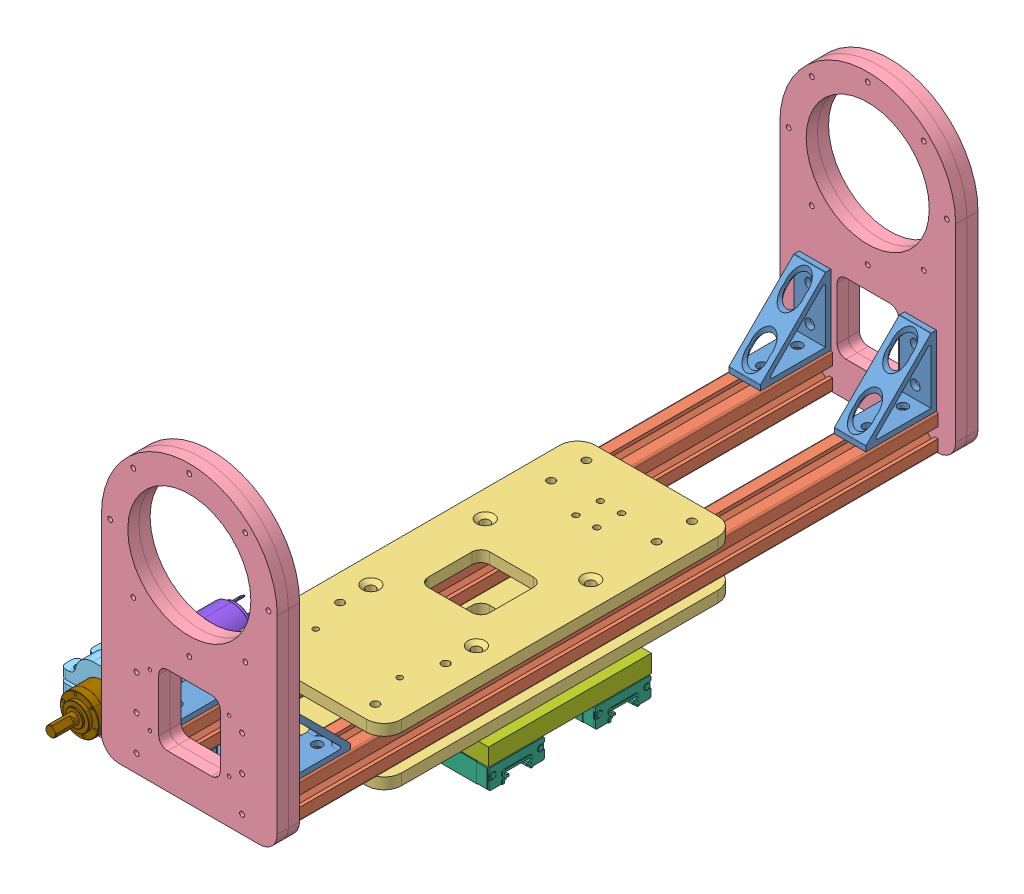
SolidWorks assembly teststand_TR2, configuration Default. Lengths in mm.
Overall size (137.28 196.05 414.76).
22 component instances, 10 part files, 39 mates.
Components (placement in the parent):
- 5537T658_T-SLOTTED FRAMING-1: 5537T658_T-SLOTTED FRAMING [5537T658] at (76.9939 380.9835 398.9275) x (0 0 -1) z (1 0 0) size (40 40 18)
- KHFS5-2020-4000-1: KHFS5-2020-4000 [14"] at (76.9939 370.9835 4025.865) size (20 20 373.06)
- teststand_TR2_adapter_Plate_Delrin-1: teststand_TR2_adapter_Plate_Delrin [Default] at (106.9939 354.6335 245.865) x (0 0 1) z (-1 0 0) size (200 6.35 90)
- teststand_TR2_Fram1-1: teststand_TR2_Fram1 [Default] at (106.9939 478.6835 19.515) size (100 167.7 6.35)
- teststand_TR2_testrig_clamp-1: teststand_TR2_testrig_clamp [Default] at (59.9939 373.4835 386.4275) x (0 0 -1) z (1 0 0) size (25 39.34 66.07)
- teststand_base_SSEB16_b_4-1: teststand_base_SSEB16_b_4 [Default] at (76.9939 328.6335 276.115) x (0 0 -1) z (1 0 0) size (32 12 42.4)
- teststand_TR2_adapter_Plate2-1: teststand_TR2_adapter_Plate2 [Default] at (106.9939 344.6335 245.865) size (101.4 10 92.5)
- KHFS5-2020-4000-2: KHFS5-2020-4000 [14"] at (136.9939 370.9835 4025.865) size (20 20 373.06)
- teststand_TR2_Fram1-2: teststand_TR2_Fram1 [Default] at (106.9939 478.6835 398.9275) size (100 167.7 6.35)
- 5537T658_T-SLOTTED FRAMING-2: 5537T658_T-SLOTTED FRAMING [5537T658] at (136.9939 380.9835 398.9275) x (0 0 -1) z (1 0 0) size (40 40 18)
- 5537T658_T-SLOTTED FRAMING-3: 5537T658_T-SLOTTED FRAMING [5537T658] at (136.9939 380.9835 25.865) x (0 0 1) z (-1 0 0) size (40 40 18)
- 5537T658_T-SLOTTED FRAMING-4: 5537T658_T-SLOTTED FRAMING [5537T658] at (76.9939 380.9835 25.865) x (0 0 1) z (-1 0 0) size (40 40 18)
- 302534_RE25_GB_20W_KL_2WE-1: 302534_RE25_GB_20W_KL_2WE [Default] at (44.4939 373.4835 366.1375) x (0 0 -1) z (1 0 0) size (78.61 25 25)
- 370792_GP22HP_3_4NM_4ST_KL-1: 370792_GP22HP_3_4NM_4ST_KL [Default] at (44.4939 373.4835 411.6275) x (0 0 -1) z (0.699856 -0.714284 0) size (62 22 22)
- teststand_base_SSEB16_b_4-2: teststand_base_SSEB16_b_4 [Default] at (136.9939 328.6335 276.115) x (0 0 -1) z (1 0 0) size (32 12 42.4)
- teststand_base_SSEB16_b_4-3: teststand_base_SSEB16_b_4 [Default] at (76.9939 328.6335 215.615) x (0 0 -1) z (1 0 0) size (32 12 42.4)
- teststand_base_SSEB16_b_4-4: teststand_base_SSEB16_b_4 [Default] at (136.9939 328.6335 215.615) x (0 0 -1) z (1 0 0) size (32 12 42.4)
- teststand_TR2_adapter_Plate_Delrin-2: teststand_TR2_adapter_Plate_Delrin [Default] at (106.9939 380.9835 245.865) x (0 0 1) z (-1 0 0) size (200 6.35 90)
- teststand_TR2_Fram1-3: teststand_TR2_Fram1 [Default] at (106.9939 478.6835 13.165) size (100 167.7 6.35)
- teststand_TR2_Fram1-4: teststand_TR2_Fram1 [Default] at (106.9939 478.6835 405.2775) size (100 167.7 6.35)
- teststand_TR2_testrig_clamp-2: teststand_TR2_testrig_clamp [Default] at (59.9939 373.4835 358.4275) x (0 0 -1) z (1 0 0) size (25 39.34 66.07)
- teststand_beltclamp-1: teststand_beltclamp [Default] at (106.9939 353.6335 178.865) x (0 0 -1) z (1 0 0) size (22 3 20)
Mates (geometry in assembly coordinates):
- Coincident14: coincident: plane of 5537T658_T-SLOTTED FRAMING-1 through (85.9939 380.9835 398.9275) normal (0 0 1); plane of teststand_TR2_Fram1-2 through (106.9939 478.6835 398.9275) normal (0 0 -1)
- Concentric12: concentric: cylinder of 5537T658_T-SLOTTED FRAMING-1 through (76.9939 390.9835 380.9275) axis (0 0 1) radius 2.75; cylinder of teststand_TR2_Fram1-2 through (76.9939 390.9835 405.2775) axis (0 0 1) radius 1.4
- Concentric13: concentric: cylinder of 5537T658_T-SLOTTED FRAMING-1 through (76.9939 410.9835 380.9275) axis (0 0 1) radius 2.75; cylinder of teststand_TR2_Fram1-2 through (76.9939 410.9835 405.2775) axis (0 0 1) radius 1.4
- Coincident10: coincident: plane of KHFS5-2020-4000-1 through (67.9939 360.9835 25.865) normal (0 -1 0); plane of teststand_TR2_adapter_Plate_Delrin-1 through (106.9939 360.9835 245.865) normal (0 1 0)
- Width5: width = 120 mm: plane of KHFS5-2020-4000-1 through (67.9939 361.9835 25.865) normal (0 0 -1); plane of KHFS5-2020-4000-1 through (67.9939 361.9835 398.9275) normal (0 0 1); plane of teststand_TR2_adapter_Plate_Delrin-1 through (61.9939 360.9835 145.865) normal (0 0 -1); plane of teststand_TR2_adapter_Plate_Delrin-1 through (61.9939 360.9835 345.865) normal (0 0 1)
- Coincident12: coincident: plane of KHFS5-2020-4000-1 through (67.9939 361.9835 25.865) normal (0 0 -1); plane of teststand_TR2_Fram1-1 through (106.9939 478.6835 25.865) normal (0 0 1)
- Concentric8: concentric: cylinder of KHFS5-2020-4000-1 through (76.9939 370.9835 25.865) axis (0 0 1) radius 2.1; cylinder of teststand_TR2_Fram1-1 through (76.9939 370.9835 25.865) axis (0 0 1) radius 1.4
- Width7: width: plane of teststand_TR2_adapter_Plate_Delrin-1 through (151.9939 360.9835 145.865) normal (1 0 0); plane of teststand_TR2_adapter_Plate_Delrin-1 through (61.9939 360.9835 145.865) normal (-1 0 0); plane of KHFS5-2020-4000-1 through (66.9939 367.9835 25.865) normal (-1 0 0); plane of KHFS5-2020-4000-2 through (146.9939 361.9835 25.865) normal (1 0 0)
- Coincident13: coincident: plane of KHFS5-2020-4000-1 through (67.9939 361.9835 398.9275) normal (0 0 1); plane of teststand_TR2_Fram1-2 through (106.9939 478.6835 398.9275) normal (0 0 -1)
- Concentric10: concentric: cylinder of KHFS5-2020-4000-1 through (76.9939 370.9835 25.865) axis (0 0 1) radius 2.1; cylinder of teststand_TR2_Fram1-2 through (76.9939 370.9835 405.2775) axis (0 0 1) radius 1.4
- Coincident18: coincident: plane of KHFS5-2020-4000-1 through (66.9939 367.9835 25.865) normal (-1 0 0); plane of teststand_TR2_testrig_clamp-1 through (66.9939 373.4835 386.4275) normal (1 0 0)
- Coincident19: coincident: plane of KHFS5-2020-4000-1 through (67.9939 360.9835 25.865) normal (0 -1 0); plane of teststand_TR2_testrig_clamp-1 through (86.9939 360.9835 398.9275) normal (0 1 0)
- Coincident9: coincident: plane of teststand_TR2_adapter_Plate_Delrin-1 through (106.9939 354.6335 245.865) normal (0 -1 0); plane of teststand_TR2_adapter_Plate2-1 through (106.9939 354.6335 245.865) normal (0 1 0)
- Concentric6: concentric: cylinder of teststand_TR2_adapter_Plate_Delrin-1 through (76.9939 360.9835 213.365) axis (0 1 0) radius 2.5527; cylinder of teststand_TR2_adapter_Plate2-1 through (76.9939 354.6335 213.365) axis (0 -1 0) radius 2
- Concentric7: concentric: cylinder of teststand_TR2_adapter_Plate_Delrin-1 through (136.9939 360.9835 278.365) axis (0 1 0) radius 2.5527; cylinder of teststand_TR2_adapter_Plate2-1 through (136.9939 354.6335 278.365) axis (0 -1 0) radius 2
- Coincident11: coincident: plane of teststand_TR2_adapter_Plate_Delrin-1 through (106.9939 360.9835 245.865) normal (0 1 0); plane of KHFS5-2020-4000-2 through (139.9939 360.9835 25.865) normal (0 -1 0)
- Width6: width = 120 mm: plane of KHFS5-2020-4000-2 through (127.9939 361.9835 25.865) normal (0 0 -1); plane of KHFS5-2020-4000-2 through (127.9939 361.9835 398.9275) normal (0 0 1); plane of teststand_TR2_adapter_Plate_Delrin-1 through (61.9939 360.9835 145.865) normal (0 0 -1); plane of teststand_TR2_adapter_Plate_Delrin-1 through (61.9939 360.9835 345.865) normal (0 0 1)
- Concentric9: concentric: cylinder of teststand_TR2_Fram1-1 through (136.9939 370.9835 25.865) axis (0 0 1) radius 1.4; cylinder of KHFS5-2020-4000-2 through (136.9939 370.9835 25.865) axis (0 0 1) radius 2.1
- Coincident16: coincident: plane of teststand_TR2_Fram1-1 through (106.9939 478.6835 25.865) normal (0 0 1); plane of 5537T658_T-SLOTTED FRAMING-3 through (127.9939 380.9835 25.865) normal (0 0 -1)
- Coincident17: coincident: plane of teststand_TR2_Fram1-1 through (106.9939 478.6835 25.865) normal (0 0 1); plane of 5537T658_T-SLOTTED FRAMING-4 through (67.9939 380.9835 25.865) normal (0 0 -1)
- Concentric16: concentric: cylinder of teststand_TR2_Fram1-1 through (76.9939 390.9835 25.865) axis (0 0 1) radius 1.4; cylinder of 5537T658_T-SLOTTED FRAMING-4 through (76.9939 390.9835 43.865) axis (0 0 -1) radius 2.75
- Concentric17: concentric: cylinder of teststand_TR2_Fram1-1 through (76.9939 410.9835 25.865) axis (0 0 1) radius 1.4; cylinder of 5537T658_T-SLOTTED FRAMING-4 through (76.9939 410.9835 43.865) axis (0 0 -1) radius 2.75
- Concentric18: concentric: cylinder of teststand_TR2_Fram1-1 through (136.9939 410.9835 25.865) axis (0 0 1) radius 1.4; cylinder of 5537T658_T-SLOTTED FRAMING-3 through (136.9939 410.9835 43.865) axis (0 0 -1) radius 2.75
- Concentric19: concentric: cylinder of teststand_TR2_Fram1-1 through (136.9939 390.9835 25.865) axis (0 0 1) radius 1.4; cylinder of 5537T658_T-SLOTTED FRAMING-3 through (136.9939 390.9835 43.865) axis (0 0 -1) radius 2.75
- Coincident20: coincident: plane of teststand_TR2_testrig_clamp-1 through (66.9939 355.9835 398.9275) normal (0 0 1); plane of teststand_TR2_Fram1-2 through (106.9939 478.6835 398.9275) normal (0 0 -1)
- Concentric21: concentric: cylinder of teststand_TR2_testrig_clamp-1 through (44.4939 373.4835 373.9275) axis (0 0 1) radius 11.075; cylinder of 370792_GP22HP_3_4NM_4ST_KL-1 through (44.4939 373.4835 427.9275) axis (0 0 -1) radius 11
- Coincident8: coincident: plane of teststand_base_SSEB16_b_4-1 through (90.6939 344.6335 283.915) normal (0 1 0); plane of teststand_TR2_adapter_Plate2-1 through (106.9939 344.6335 245.865) normal (0 -1 0)
- Concentric1: concentric: cylinder of teststand_base_SSEB16_b_4-3 through (66.9939 336.9236 203.115) axis (0 1 0) radius 1.2295; cylinder of teststand_TR2_adapter_Plate2-1 through (66.9939 354.6335 203.115) axis (0 -1 0) radius 1.5
- Concentric3: concentric: cylinder of teststand_base_SSEB16_b_4-2 through (146.9939 336.9236 288.615) axis (0 1 0) radius 1.2295; cylinder of teststand_TR2_adapter_Plate2-1 through (146.9939 354.6335 288.615) axis (0 -1 0) radius 1.5
- Concentric11: concentric: cylinder of KHFS5-2020-4000-2 through (136.9939 370.9835 25.865) axis (0 0 1) radius 2.1; cylinder of teststand_TR2_Fram1-2 through (136.9939 370.9835 405.2775) axis (0 0 1) radius 1.4
- Concentric14: concentric: cylinder of teststand_TR2_Fram1-2 through (136.9939 410.9835 405.2775) axis (0 0 1) radius 1.4; cylinder of 5537T658_T-SLOTTED FRAMING-2 through (136.9939 410.9835 380.9275) axis (0 0 1) radius 2.75
- Concentric15: concentric: cylinder of teststand_TR2_Fram1-2 through (136.9939 390.9835 405.2775) axis (0 0 1) radius 1.4; cylinder of 5537T658_T-SLOTTED FRAMING-2 through (136.9939 390.9835 380.9275) axis (0 0 1) radius 2.75
- Coincident15: coincident: plane of teststand_TR2_Fram1-2 through (106.9939 478.6835 398.9275) normal (0 0 -1); plane of 5537T658_T-SLOTTED FRAMING-2 through (145.9939 380.9835 398.9275) normal (0 0 1)
- Coincident21: coincident: plane of 302534_RE25_GB_20W_KL_2WE-1 through (44.4939 373.4835 365.9275) normal (0 0 1); plane of 370792_GP22HP_3_4NM_4ST_KL-1 through (44.4939 373.4835 365.9275) normal (0 0 -1)
- Concentric20: concentric: cylinder of 302534_RE25_GB_20W_KL_2WE-1 through (44.4939 373.4835 367.951) axis (0 0 -1) radius 12.5; cylinder of 370792_GP22HP_3_4NM_4ST_KL-1 through (44.4939 373.4835 427.9275) axis (0 0 -1) radius 11
- Coincident23: coincident: plane of teststand_TR2_Fram1-4 through (106.9939 478.6835 411.6275) normal (0 0 1); plane of 370792_GP22HP_3_4NM_4ST_KL-1 through (44.4939 373.4835 411.6275) normal (0 0 1)
- Distance1: distance = 30 mm: plane of teststand_TR2_adapter_Plate_Delrin-1 through (61.9939 360.9835 145.865) normal (0 0 -1); plane of teststand_beltclamp-1 through (116.9939 354.6335 175.865) normal (0 0 1)
- Coincident24: coincident: plane of teststand_TR2_adapter_Plate_Delrin-1 through (106.9939 354.6335 245.865) normal (0 -1 0); plane of teststand_beltclamp-1 through (116.9939 354.6335 175.865) normal (0 1 0); plane of teststand_beltclamp-1; plane of teststand_TR2_adapter_Plate_Delrin-1
- Distance2: distance = 35 mm: plane of teststand_beltclamp-1 through (116.9939 353.6335 178.865) normal (1 0 0); plane of teststand_TR2_adapter_Plate_Delrin-1 through (151.9939 360.9835 145.865) normal (1 0 0)
